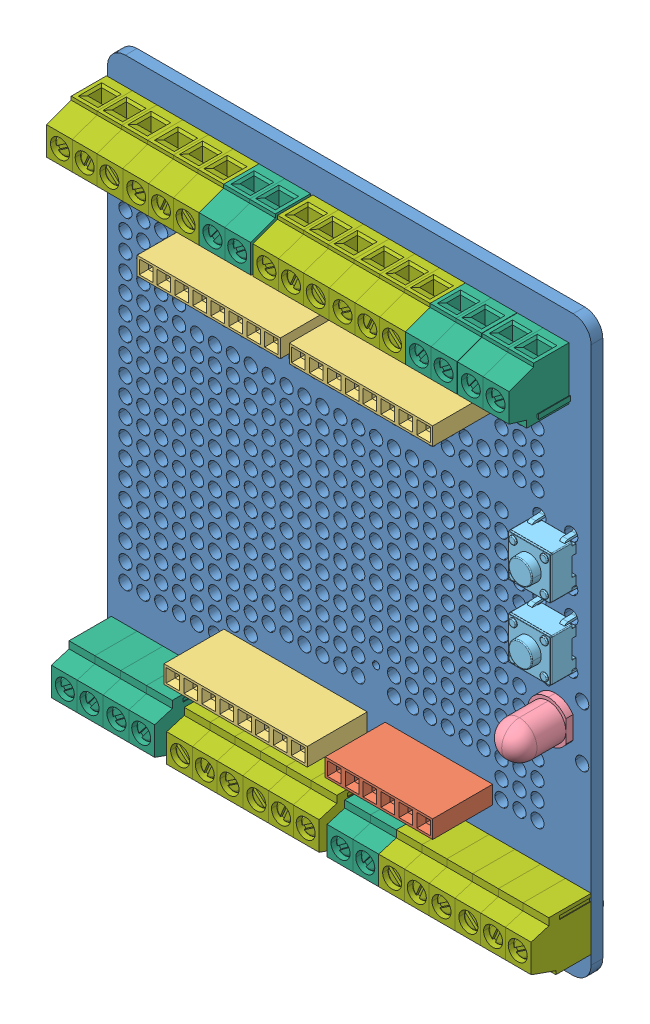
SolidWorks assembly ProtoScrewShield, configuration Default. Lengths in mm.
Overall size (68.72 81.28 18.96).
23 component instances, 7 part files, 0 mates.
Components (placement in the parent):
- ProtoScrewShield.STEP-1: ProtoScrewShield.STEP [Default] at origin size (68.72 81.28 18.96)
  - ProtoScrewShield PCB.STEP-1: ProtoScrewShield PCB.STEP [Default] at (-66.799 -25.1325 5.7935) size (68.58 81.28 1.65)
  - Female Header- Stackable_6 Pin.STEP-1: Female Header- Stackable_6 Pin.STEP [Default] at (-13.459 -8.6225 15.9445) x (1 0 0) z (0 1 0) size (15.24 18.96 2.54)
  - Female Header- Stackable_8 Pin.STEP-1: Female Header- Stackable_8 Pin.STEP [Default] at (-31.239 -8.6225 15.9445) x (1 0 0) z (0 1 0) size (20.32 18.96 2.54)
  - Female Header- Stackable_8 Pin.STEP-2: Female Header- Stackable_8 Pin.STEP [Default] at (-13.459 39.6375 15.9445) x (1 0 0) z (0 1 0) size (20.32 18.96 2.54)
  - Female Header- Stackable_8 Pin.STEP-3: Female Header- Stackable_8 Pin.STEP [Default] at (-35.049 39.6375 15.9445) x (1 0 0) z (0 1 0) size (20.32 18.96 2.54)
  - led_IR_Trimmed Leads.STEP-1: led_IR_Trimmed Leads.STEP [Default] at (-3.299 5.3286 927.0338) x (-1 0 0) z (0 1 0) size (5.45 10.78 5.9)
  - tactileswitch-short.STEP-1: tactileswitch-short.STEP [Default] at (-3.3308 15.4536 7.4445) x (0 1 0) z (1 0 0) size (7.69 8.33 6.01)
  - tactileswitch-short.STEP-2: tactileswitch-short.STEP [Default] at (-3.3308 25.5874 7.4445) x (0 1 0) z (1 0 0) size (7.69 8.33 6.01)
  - 2 Pin PCB Terminal Block.STEP-1: 2 Pin PCB Terminal Block.STEP [Default] at (-62.4391 -17.5089 7.4445) x (-1 0 0) z (0 0 1) size (7.51 7.5 12)
  - 3 Pin PCB Terminal Block.STEP-1: 3 Pin PCB Terminal Block.STEP [Default] at (-33.3793 -17.5089 7.4445) x (-1 0 0) z (0 0 1) size (11.01 7.5 12)
  - 2 Pin PCB Terminal Block.STEP-2: 2 Pin PCB Terminal Block.STEP [Default] at (-55.1191 -17.5089 7.4445) x (-1 0 0) z (0 0 1) size (7.51 7.5 12)
  - 3 Pin PCB Terminal Block.STEP-2: 3 Pin PCB Terminal Block.STEP [Default] at (-44.1893 -17.5089 7.4445) x (-1 0 0) z (0 0 1) size (11.01 7.5 12)
  - 3 Pin PCB Terminal Block.STEP-3: 3 Pin PCB Terminal Block.STEP [Default] at (-14.124 -17.5089 7.4445) x (-1 0 0) z (0 0 1) size (11.01 7.5 12)
  - 2 Pin PCB Terminal Block.STEP-3: 2 Pin PCB Terminal Block.STEP [Default] at (-23.349 -17.5089 7.4445) x (-1 0 0) z (0 0 1) size (7.51 7.5 12)
  - 3 Pin PCB Terminal Block.STEP-4: 3 Pin PCB Terminal Block.STEP [Default] at (-3.314 -17.5089 7.4445) x (-1 0 0) z (0 0 1) size (11.01 7.5 12)
  - 2 Pin PCB Terminal Block.STEP-4: 2 Pin PCB Terminal Block.STEP [Default] at (-5.1718 48.5238 7.4445) size (7.51 7.5 12)
  - 2 Pin PCB Terminal Block.STEP-5: 2 Pin PCB Terminal Block.STEP [Default] at (-12.54 48.5238 7.4445) size (7.51 7.5 12)
  - 3 Pin PCB Terminal Block.STEP-5: 3 Pin PCB Terminal Block.STEP [Default] at (-32.575 48.5238 7.4445) size (11.01 7.5 12)
  - 2 Pin PCB Terminal Block.STEP-6: 2 Pin PCB Terminal Block.STEP [Default] at (-41.8046 48.5238 7.4445) size (7.51 7.5 12)
  - 3 Pin PCB Terminal Block.STEP-6: 3 Pin PCB Terminal Block.STEP [Default] at (-21.765 48.5238 7.4445) size (11.01 7.5 12)
  - 3 Pin PCB Terminal Block.STEP-7: 3 Pin PCB Terminal Block.STEP [Default] at (-51.0296 48.5238 7.4445) size (11.01 7.5 12)
  - 3 Pin PCB Terminal Block.STEP-8: 3 Pin PCB Terminal Block.STEP [Default] at (-61.8396 48.5238 7.4445) size (11.01 7.5 12)
